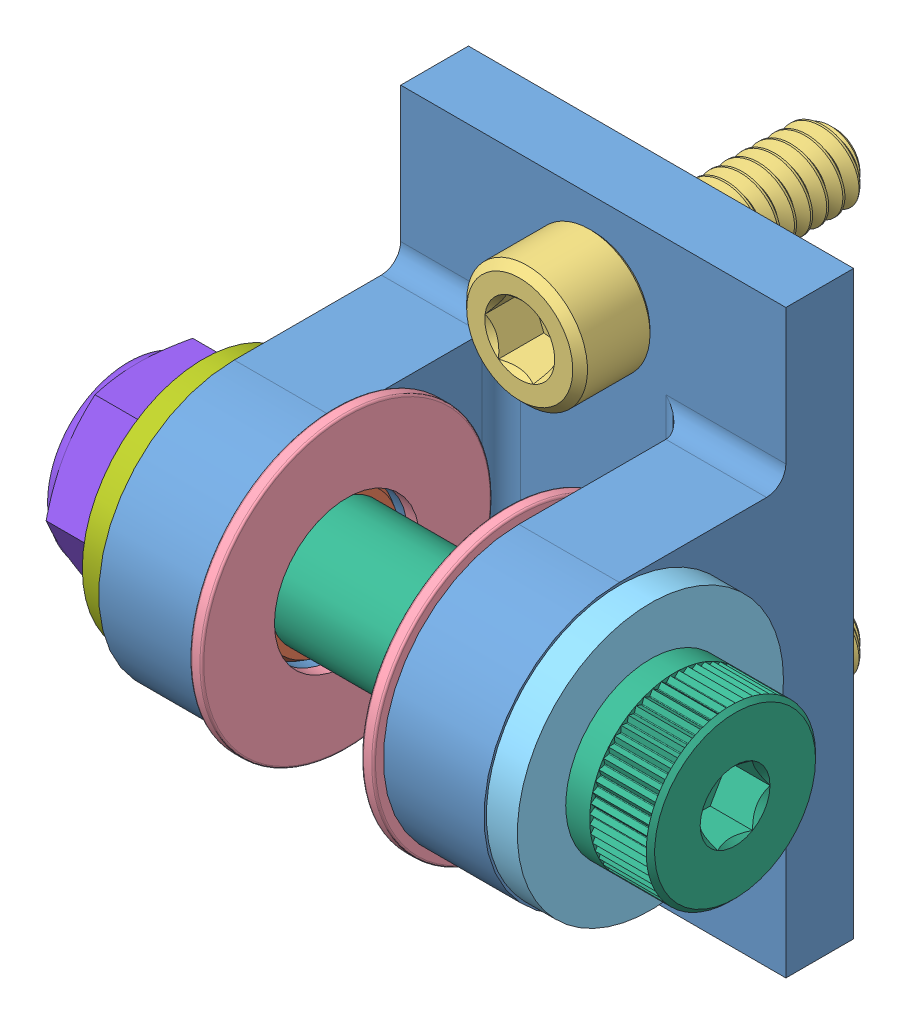
SolidWorks assembly Tab Assembly, configuration Default. Lengths in mm.
Overall size (42.53 38.1 36.71).
11 component instances, 8 part files, 20 mates.
Components (placement in the parent):
- Link Tab (LK-1)-1: Link Tab (LK-1) [Default] at (-17.7971 -3.9275 -0.0689) size (25.27 38.1 24.26)
- Tab Sleeve Bushing (igus TSI-0506-04)-1: Tab Sleeve Bushing (igus TSI-0506-04) [Default] at (-5.1606 -3.9275 15.2981) x (0 0 1) z (-1 0 0) size (9.53 9.53 6.35)
- Tab Sleeve Bushing (igus TSI-0506-04)-2: Tab Sleeve Bushing (igus TSI-0506-04) [Default] at (-30.4336 -3.9275 15.2981) x (0 -0.924225 -0.381849) z (1 0 0) size (9.53 9.53 6.35)
- Tab Bolts (MMC 91251A244)-1: Tab Bolts (MMC 91251A244) [91251A244] at (-17.7971 9.4075 -11.4989) x (-0.923728 -0.383049 0) z (0 0 -1) size (7.92 7.92 21.32)
- Tab Bolts (MMC 91251A244)-2: Tab Bolts (MMC 91251A244) [91251A244] at (-17.7971 -17.2625 -11.4989) x (-0.923728 -0.383049 0) z (0 0 -1) size (7.92 7.92 21.32)
- Linkage Thrust Bearing (MSC 06455364)-1: Linkage Thrust Bearing (MSC 06455364) [Default] at (-12.5584 -3.9275 15.2981) x (0 0 -1) z (1 0 0) size (19.05 19.05 0.79)
- Linkage Thrust Bearing (MSC 06455364)-2: Linkage Thrust Bearing (MSC 06455364) [Default] at (-23.8296 -3.9275 15.2981) x (0 0 -1) z (1 0 0) size (19.05 19.05 0.79)
- SAE 0.3125 Washer (MMC 96659A107)-1: SAE 0.3125 Washer (MMC 96659A107) [96659A107] at (-3.1286 -3.9275 15.2981) x (0 1 0) z (0 0 1) size (17.46 2.03 17.46)
- Link Pivot Shoulder Bolt (MMC 91259A583)-1: Link Pivot Shoulder Bolt (MMC 91259A583) [91259A583] at (-3.1286 -3.9275 15.2981) x (0 -1 0) z (0 0 1) size (11.11 42.53 11.11)
- SAE 025 Washer (MMC 91083A029)-1: SAE 025 Washer (MMC 91083A029) [91083A029] at (-32.4656 -3.9275 15.2981) size (2.03 15.88 15.88)
- Pivot Nylok (MMC 94945A205)-1: Pivot Nylok (MMC 94945A205) [94945A205] at (-32.4656 -3.9275 15.2981) x (0 1 0) z (0 0 1) size (11.11 5.35 12.83)
Mates (geometry in assembly coordinates):
- Concentric1: concentric aligned: cylinder of Link Tab (LK-1)-1 through (-30.4336 -3.9275 15.2981) axis (1 0 0) radius 4.7942; cylinder of Tab Sleeve Bushing (igus TSI-0506-04)-1 through (-11.5106 -3.9275 15.2981) axis (1 0 0) radius 4.7625
- Coincident1: coincident aligned: plane of Link Tab (LK-1)-1 through (-5.1606 -22.9775 4.3761) normal (1 0 0); plane of Tab Sleeve Bushing (igus TSI-0506-04)-1 through (-5.1606 -3.9275 19.5555) normal (1 0 0)
- Concentric2: concentric anti-aligned: cylinder of Link Tab (LK-1)-1 through (-30.4336 -3.9275 15.2981) axis (1 0 0) radius 4.7942; cylinder of Tab Sleeve Bushing (igus TSI-0506-04)-2 through (-24.0836 -3.9275 15.2981) axis (-1 0 0) radius 4.7625
- Coincident2: coincident aligned: plane of Link Tab (LK-1)-1 through (-30.4336 -22.9775 4.3761) normal (-1 0 0); plane of Tab Sleeve Bushing (igus TSI-0506-04)-2 through (-30.4336 -7.8623 13.6724) normal (-1 0 0)
- Concentric3: concentric: cylinder of Link Tab (LK-1)-1 through (-17.7971 9.4075 -0.0689) axis (0 0 1) radius 2.8067; cylinder of Tab Bolts (MMC 91251A244)-1 through (-17.7971 9.4075 9.2021) axis (0 0 -1) radius 3.9624
- Coincident3: coincident anti-aligned: plane of Link Tab (LK-1)-1 through (-17.7971 -3.9275 4.3761) normal (0 0 1); plane of Tab Bolts (MMC 91251A244)-1 through (-17.7971 9.4075 4.3761) normal (0 0 -1)
- Concentric4: concentric: cylinder of Link Tab (LK-1)-1 through (-17.7971 -17.2625 -0.0689) axis (0 0 1) radius 2.8067; cylinder of Tab Bolts (MMC 91251A244)-2 through (-17.7971 -17.2625 9.2021) axis (0 0 -1) radius 3.9624
- Coincident4: coincident anti-aligned: plane of Link Tab (LK-1)-1 through (-17.7971 -3.9275 4.3761) normal (0 0 1); plane of Tab Bolts (MMC 91251A244)-2 through (-17.7971 -17.2625 4.3761) normal (0 0 -1)
- Concentric5: concentric anti-aligned: cylinder of Tab Sleeve Bushing (igus TSI-0506-04)-1 through (-11.5106 -3.9275 15.2981) axis (1 0 0) radius 3.9688; cylinder of Linkage Thrust Bearing (MSC 06455364)-1 through (-11.7646 -3.9275 15.2981) axis (-1 0 0) radius 4.7625
- Coincident5: coincident anti-aligned: plane of Link Tab (LK-1)-1 through (-11.7646 -12.8175 24.1881) normal (-1 0 0); plane of Linkage Thrust Bearing (MSC 06455364)-1 through (-11.7646 -3.9275 15.2981) normal (1 0 0)
- Concentric6: concentric aligned: cylinder of Tab Sleeve Bushing (igus TSI-0506-04)-2 through (-24.0836 -3.9275 15.2981) axis (-1 0 0) radius 3.9688; cylinder of Linkage Thrust Bearing (MSC 06455364)-2 through (-23.0359 -3.9275 15.2981) axis (-1 0 0) radius 4.7625
- Coincident6: coincident anti-aligned: plane of Link Tab (LK-1)-1 through (-23.8296 -12.8175 24.1881) normal (1 0 0); plane of Linkage Thrust Bearing (MSC 06455364)-2 through (-23.8296 -3.9275 15.2981) normal (-1 0 0)
- Concentric7: concentric anti-aligned: cylinder of Tab Sleeve Bushing (igus TSI-0506-04)-1 through (-11.5106 -3.9275 15.2981) axis (1 0 0) radius 3.9688; cylinder of SAE 0.3125 Washer (MMC 96659A107)-1 through (-3.1286 -3.9275 15.2981) axis (-1 0 0) radius 4.3688
- Coincident7: coincident anti-aligned: plane of Link Tab (LK-1)-1 through (-5.1606 -22.9775 4.3761) normal (1 0 0); plane of SAE 0.3125 Washer (MMC 96659A107)-1 through (-5.1606 -3.9275 15.2981) normal (-1 0 0)
- Concentric8: concentric: cylinder of SAE 0.3125 Washer (MMC 96659A107)-1 through (-3.1286 -3.9275 15.2981) axis (-1 0 0) radius 4.3688; cylinder of Link Pivot Shoulder Bolt (MMC 91259A583)-1 through (-3.1286 -3.9275 15.2981) axis (-1 0 0) radius 3.9688
- Coincident8: coincident anti-aligned: plane of SAE 0.3125 Washer (MMC 96659A107)-1 through (-3.1286 -3.9275 15.2981) normal (1 0 0); plane of Link Pivot Shoulder Bolt (MMC 91259A583)-1 through (-3.1286 -3.9275 15.2981) normal (-1 0 0)
- Concentric9: concentric aligned: cylinder of Tab Sleeve Bushing (igus TSI-0506-04)-2 through (-24.0836 -3.9275 15.2981) axis (-1 0 0) radius 3.9688; cylinder of SAE 025 Washer (MMC 91083A029)-1 through (-30.4336 -3.9275 15.2981) axis (-1 0 0) radius 3.5687
- Coincident9: coincident anti-aligned: plane of Link Tab (LK-1)-1 through (-30.4336 -22.9775 4.3761) normal (-1 0 0); plane of SAE 025 Washer (MMC 91083A029)-1 through (-30.4336 -3.9275 15.2981) normal (1 0 0)
- Concentric10: concentric: cylinder of SAE 025 Washer (MMC 91083A029)-1 through (-30.4336 -3.9275 15.2981) axis (-1 0 0) radius 7.9375; cylinder of Pivot Nylok (MMC 94945A205)-1 through (-36.8413 -3.9275 15.2981) axis (1 0 0) radius 2.6099
- Coincident10: coincident anti-aligned: plane of SAE 025 Washer (MMC 91083A029)-1 through (-32.4656 -3.9275 15.2981) normal (-1 0 0); plane of Pivot Nylok (MMC 94945A205)-1 through (-32.4656 7.185 15.2981) normal (1 0 0)
